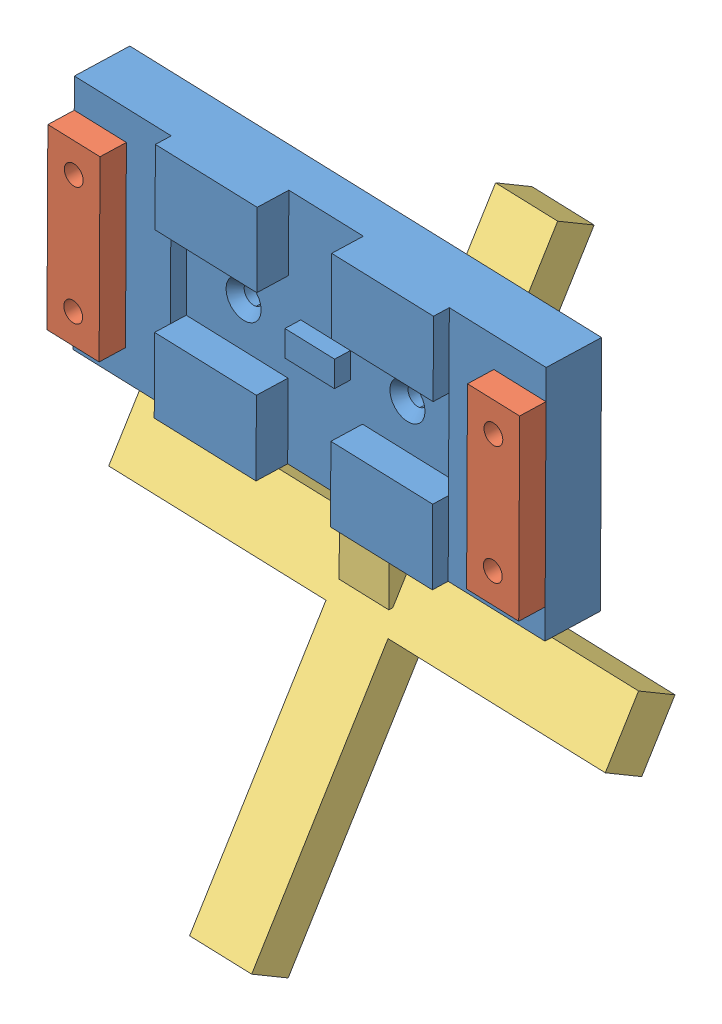
SolidWorks assembly Assembly, configuration Default. Lengths in mm.
Overall size (102.29 120.53 67.58).
3 component instances, 3 part files, 6 mates.
Components (placement in the parent):
- Mount-1: Mount [Default] at (13.5634 -12.9256 -42.6198) x (-0.99953 0.003531 -0.030458) z (-0.030453 0.001451 0.999535) size (95 46.3 13.5)
- Plate-1: Plate [Default] at (13.2284 -12.9097 -31.6249) x (0.99953 -0.003531 0.030458) z (0.030453 -0.001451 -0.999535) size (95 34.73 5)
- stand 30 degree-1: stand 30 degree [Default] at (13.5634 -12.9256 -42.6198) x (0.99953 -0.003531 0.030458) z (-0.030453 0.001451 0.999535) size (100 103.59 64.43)
Mates (geometry in assembly coordinates):
- Concentric3: concentric aligned: cylinder of bottomMountPlate-1 through (-28.4797 -24.3622 -51.3876) axis (0.030453 -0.001451 -0.999535) radius 1.8986; cylinder of topMountPlate-1 through (-28.7995 -24.347 -40.8925) axis (0.030453 -0.001451 -0.999535) radius 1.8986
- Coincident3: coincident aligned: cylinder of bottomMountPlate-1 through (-28.397 -1.2124 -51.4187) axis (0.030453 -0.001451 -0.999535) radius 1.8986; circle of topMountPlate-1
- Coincident4: coincident anti-aligned: plane of bottomMountPlate-1 through (13.472 -12.9213 -39.6212) normal (-0.030453 0.001451 0.999535); plane of topMountPlate-1 through (13.472 -12.9213 -39.6212) normal (0.030453 -0.001451 -0.999535)
- Concentric4: concentric anti-aligned: cylinder of bottomMountPlate-1 through (-2.9289 -12.8674 -43.1224) axis (-0.030453 0.001451 0.999535) radius 1.8986; cylinder of stand-1 through (-2.396 -12.8928 -60.6142) axis (0.030453 -0.001451 -0.999535) radius 1.8986
- Concentric5: concentric anti-aligned: cylinder of bottomMountPlate-1 through (30.0556 -12.9839 -42.1172) axis (-0.030453 0.001451 0.999535) radius 1.8986; cylinder of stand-1 through (30.5885 -13.0093 -59.6091) axis (0.030453 -0.001451 -0.999535) radius 1.8986
- Coincident5: coincident anti-aligned: plane of bottomMountPlate-1 through (13.7918 -12.9365 -50.1163) normal (0.030453 -0.001451 -0.999535); plane of stand-1 through (-8.6753 -6.6071 -50.81) normal (-0.030453 0.001451 0.999535)
